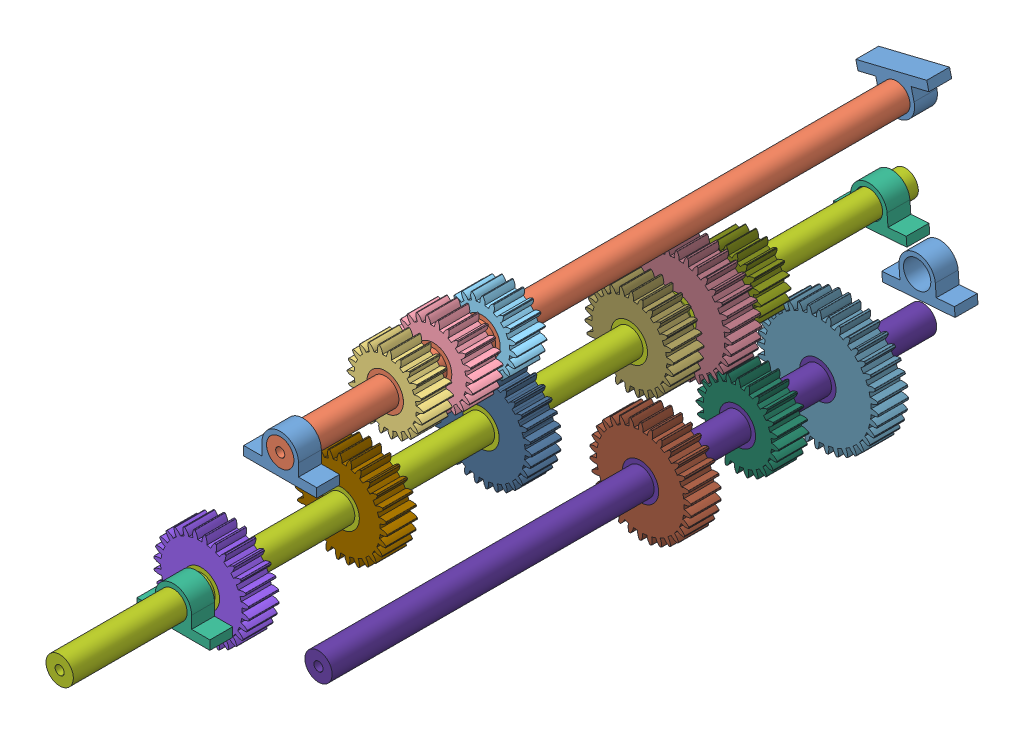
SolidWorks assembly meshingorder, configuration Default. Lengths in mm.
Overall size (216.68 301.08 940.52).
20 component instances, 17 part files, 46 mates.
Components (placement in the parent):
- input hub-1: input hub [Default] at (-7.2173 26.4607 64.1098) size (80 43.42 25)
- input shaft-1: input shaft [Default] at (-7.2173 49.8806 -88.5886) x (0 0 -1) z (0.63223 0.774781 0) size (700 40 40)
- g1h-1: g1h [Default] at (-7.2173 49.8806 -58.8602) x (0.468719 -0.883347 0) z (0 0 1) size (83.95 83.61 33.04)
- input hub-2: input hub [Default] at (-12.7668 72.6335 -610.8902) x (-0.97152 -0.236957 0) z (0 0 1) size (80 43.42 25)
- g3h-1: g3h [Default] at (-7.2173 49.8806 -111.8302) x (0.676136 0.736777 0) z (0 0 1) size (87.32 87.24 33.04)
- g5h-1: g5h [Default] at (-7.2173 49.8806 -164.8002) x (0.676136 0.736777 0) z (0 0 1) size (76.71 76.71 32.97)
- intermediateshaft hub-1: intermediateshaft hub [Default] at (-8.2117 -60.4938 180.1317) x (0.999999 0 0.001021) z (-0.001021 0 0.999999) size (80 43.42 25)
- intermediateshaft hub-2: intermediateshaft hub [Default] at (-5.6073 -60.4224 -581.045) x (0.996951 0.078021 0.001018) z (-0.001021 0 0.999999) size (80 43.42 25)
- helloworld1-1: helloworld1 [Default] at (-8.1374 -37.0739 107.3798) x (0.001021 0 -0.999999) z (0.256209 0.966621 0.000262) size (925.65 41.04 41.04)
- g2h2-1: g2h2 [Default] at (-8.1723 -37.0739 141.5601) x (0.256209 0.966621 0.000262) z (-0.001021 0 0.999999) size (104.95 104.95 33.05)
- g4h2-1: g4h2 [Default] at (-8.0161 -37.0739 -11.4098) x (0.740272 -0.672308 0.000756) z (-0.001021 0 0.999999) size (101.31 101.36 33.05)
- g6h2-1: g6h2 [Default] at (-7.8599 -37.0739 -164.3798) x (0.924153 -0.382021 0.000943) z (-0.001021 0 0.999999) size (111.52 111.21 33.05)
- input hub-4: input hub [Default] at (95.4929 -52.5065 -532.8709) x (0.996949 0.078021 0.002415) z (-0.002414 -0.000109 0.999997) size (80 43.42 25)
- g8h3-1: g8h3 [Default] at (57.1012 -110.6872 -274.2508) x (-0.734951 0.678118 -0.0017) z (-0.002413 -0.000109 0.999997) size (112 111.57 33.05)
- g7h2-1: g7h2 [Default] at (-7.6941 -37.0739 -326.8315) x (0.814736 -0.579832 0.000832) z (-0.001021 0 0.999999) size (97.97 97.7 33.05)
- g9h2-1: g9h2 [Default] at (-7.64 -37.0739 -379.8015) x (-0.157045 -0.987591 -0.00016) z (-0.001021 0 0.999999) size (119 119 33.05)
- g12h3-1: g12h3 [Default] at (57.5691 -110.6661 -468.1602) x (0.995722 0.092374 0.002413) z (-0.002413 -0.000109 0.999997) size (132.83 132.83 33.05)
- g10h3-3: g10h3 [Default] at (57.3568 -110.6757 -380.1905) x (0.971382 -0.237512 0.002318) z (-0.002413 -0.000109 0.999997) size (90.96 90.96 33.05)
- g11h2-1: g11h2 [Default] at (-7.5858 -37.0739 -432.8547) x (-0.929793 0.368082 -0.000949) z (-0.001021 0 0.999999) size (76.85 76.85 33.02)
- outputshaft-2: outputshaft [Default] at (57.0767 -110.6883 -264.0973) x (0.002413 0.000109 -0.999997) z (0.823959 0.566646 0.00205) size (660.79 40 40)
Mates (geometry in assembly coordinates):
- Concentric1: concentric anti-aligned: cylinder of input hub-1 through (-7.2173 49.8806 89.1098) axis (0 0 -1) radius 15; cylinder of input shaft-1 through (-7.2173 49.8806 26.0145) axis (0 0 1) radius 15
- Coincident1: coincident aligned: circle of input hub-1; circle of input shaft-1
- Concentric2: concentric aligned: cylinder of input shaft-1 through (-7.2173 49.8806 26.0145) axis (0 0 1) radius 20; cylinder of g1h-1 through (-7.2173 49.8806 -58.8934) axis (0 0 1) radius 20
- Coincident2: coincident aligned: circle of input shaft-1; circle of g1h-1
- Concentric3: concentric anti-aligned: cylinder of input shaft-1 through (-7.2173 49.8806 26.0145) axis (0 0 1) radius 15; cylinder of input hub-2 through (-7.2173 49.8806 -585.8902) axis (0 0 -1) radius 15
- Coincident3: coincident aligned: circle of input shaft-1; circle of input hub-2
- Lock1: lock: unknown of input shaft-1; unknown of g1h-1
- Coincident4: coincident aligned: circle of input shaft-1; circle of g3h-1
- Lock2: lock: unknown of input shaft-1; unknown of g3h-1
- Coincident5: coincident aligned: circle of input shaft-1; circle of g5h-1
- Lock3: lock: unknown of input shaft-1; unknown of g5h-1
- Parallel1: parallel aligned: plane of input hub-1 through (32.7827 26.4607 89.1098) normal (0 -1 0); plane of intermediateshaft hub-1 through (31.7628 -60.4938 205.1725) normal (0 -1 0)
- Concentric4: concentric: cylinder of intermediateshaft hub-1 through (-8.2372 -37.0739 205.1317) axis (0.001021 0 -0.999999) radius 15; cylinder of helloworld1-1 through (-8.2418 -37.0739 209.6596) axis (-0.001021 0 0.999999) radius 15
- Coincident7: coincident: circle of helloworld1-1; circle of g2h2-1
- Lock4: lock: unknown of helloworld1-1; unknown of g2h2-1
- Concentric6: concentric aligned: circle of intermediateshaft hub-2; cylinder of helloworld1-1 through (-8.2418 -37.0739 209.6596) axis (-0.001021 0 0.999999) radius 14.1383
- Concentric7: concentric: cylinder of helloworld1-1 through (-8.2418 -37.0739 209.6596) axis (-0.001021 0 0.999999) radius 20; cylinder of g4h2-1 through (-8.0161 -37.0739 -11.4501) axis (-0.001021 0 0.999999) radius 20
- Coincident9: coincident: circle of helloworld1-1; circle of g4h2-1
- Coincident10: coincident: circle of helloworld1-1; circle of g6h2-1
- Lock6: lock: unknown of helloworld1-1; unknown of g6h2-1
- Parallel3: parallel aligned: plane of intermediateshaft hub-2 through (34.2452 -57.3016 -556.0043) normal (0.078021 -0.996952 0.00008); plane of input hub-4 through (135.3105 -49.3884 -507.7744) normal (0.078021 -0.996952 0.00008)
- Coincident14: coincident: circle of helloworld1-1; circle of g7h2-1
- Lock8: lock: unknown of helloworld1-1; unknown of g7h2-1
- Coincident15: coincident: circle of helloworld1-1; circle of g9h2-1
- Lock9: lock: unknown of helloworld1-1; unknown of g9h2-1
- Concentric16: concentric: circle of helloworld1-1; circle of g11h2-1
- Concentric17: concentric aligned: circle of helloworld1-1; circle of g11h2-1
- Lock14: lock: unknown of helloworld1-1; unknown of g11h2-1
- Concentric22: concentric: cylinder of input hub-4 through (93.6053 -29.1607 -507.8729) axis (0.002414 0.000109 -0.999997) radius 15; cylinder of outputshaft-2 through (56.7344 -110.7038 -122.2683) axis (-0.002413 -0.000109 0.999997) radius 15
- Parallel5: parallel: plane of intermediateshaft hub-2 through (34.2452 -57.3016 -556.0043) normal (0.078021 -0.996952 0.00008); plane of input hub-4 through (135.3105 -49.3884 -507.7744) normal (0.078021 -0.996952 0.00008)
- Coincident25: coincident: circle of g12h3-1; circle of outputshaft-2
- Lock15: lock: unknown of g12h3-1; unknown of outputshaft-2
- Coincident28: coincident: circle of g10h3-3; circle of outputshaft-2
- Coincident29: coincident: circle of g8h3-1; circle of outputshaft-2
- Lock16: lock: unknown of g10h3-3; unknown of outputshaft-2
- Parallel6: parallel aligned: plane of intermediateshaft hub-2 through (34.2452 -57.3016 -556.0043) normal (0.078021 -0.996952 0.00008); plane of input hub-4 through (135.3105 -49.3884 -507.7744) normal (0.078021 -0.996952 0.00008)
- Lock18: lock: unknown of helloworld1-1; unknown of g4h2-1
- Lock19: lock: unknown of g8h3-1; unknown of outputshaft-2
- Lock20: lock: unknown of helloworld1-1; unknown of g4h2-1
- Lock21: lock: unknown of helloworld1-1; unknown of g2h2-1
- GearMate6: gear = 94.5 : 80.5 mm: circle of g3h-1; circle of g4h2-1
- GearMate7: gear = 112 : 84 mm: circle of g10h3-3; circle of g9h2-1
- Lock22: lock: unknown of helloworld1-1; unknown of g4h2-1
- Lock23: lock: unknown of helloworld1-1; unknown of g7h2-1
- GearMate12: gear = 105 : 70 mm: circle of g5h-1; circle of g6h2-1
- GearMate16: gear = 84 : 112 mm: circle of g9h2-1; circle of g10h3-3
